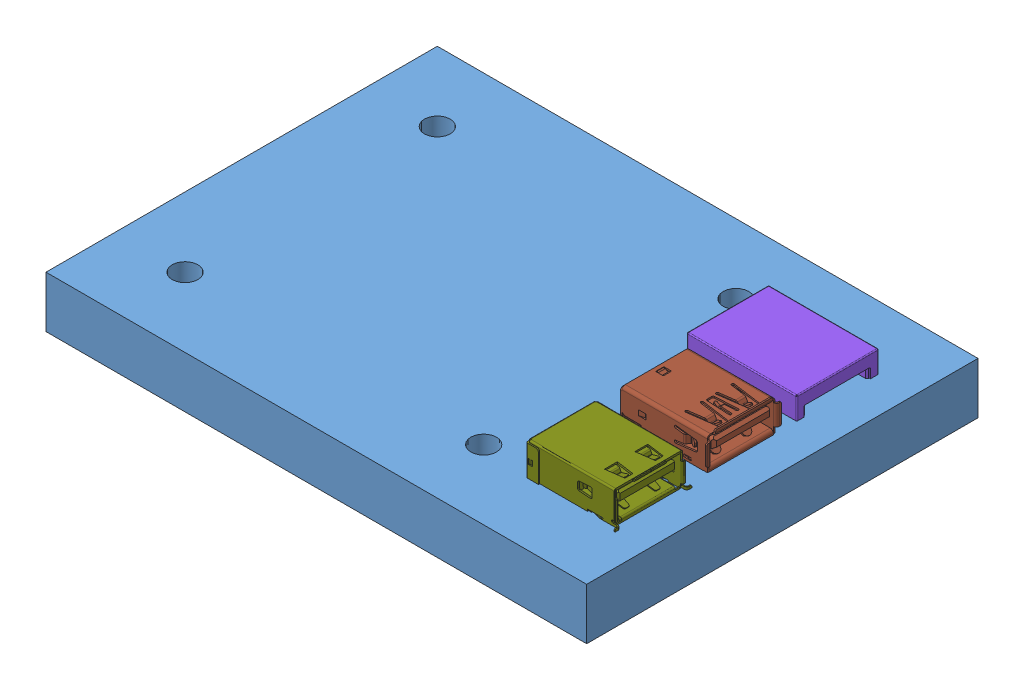
SolidWorks assembly Pi Alignment, configuration Default. Lengths in mm.
Overall size (105 19.92 76).
21 component instances, 19 part files, 7 mates.
Components (placement in the parent):
- Raspberry Pi 4 Model B-1: Raspberry Pi 4 Model B [Default] at origin size (89 19.92 58.4)
  - PCB, RPi4ModelB.STEP-1: PCB, RPi4ModelB.STEP [Default] at origin size (85 1.6 56)
  - Broadcom BCM2711B0 CPU, RPi4ModelB.STEP-1: Broadcom BCM2711B0 CPU, RPi4ModelB.STEP [Default] at (-13.25 0.8 -4.5) size (15 2.3 15)
  - 2.54 mm DUPONT MALE PIN HEADER, POE, 2X2, RPi4ModelB.STEP-1: 2.54 mm DUPONT MALE PIN HEADER, POE, 2X2, RPi4ModelB.STEP [Default] at (19 0.8 -18.36) size (5.08 11.3 5.08)
  - 2.54 mm DUPONT MALE PIN HEADER, IO, 2X20, RPi4ModelB.STEP-1: 2.54 mm DUPONT MALE PIN HEADER, IO, 2X20, RPi4ModelB.STEP [Default] at (-10 0.8 -24.5) size (50.8 11.3 5.08)
  - Camera Connector, RPi4ModelB.STEP-1: Camera Connector, RPi4ModelB.STEP [Default] at (4 0.8 16.5) x (0 0 -1) z (1 0 0) size (22.4 5.68 5.07)
  - Microphone Plug, RPi4ModelB.STEP-1: Microphone Plug, RPi4ModelB.STEP [Default] at (11.5 0.8 21.65) size (7.23 7.55 15)
  - Display Connector, RPi4ModelB.STEP-1: Display Connector, RPi4ModelB.STEP [Default] at (-38.5 0.8 0) x (0 0 1) z (-1 0 0) size (22.4 5.68 5.07)
  - Gigabit Ethernet Port, RPi4ModelB.STEP-1: Gigabit Ethernet Port, RPi4ModelB.STEP [Default] at (45.5 7.55 -17.75) x (0 0 -1) z (1 0 0) size (16.33 17.24 21.6)
  - Female Micro HDMI Connector, RPi4ModelB.STEP-1: Female Micro HDMI Connector, RPi4ModelB.STEP [Default] at (-3 0.8 27.3875) size (6.5 3.51 7.5)
  - Female Micro HDMI Connector, RPi4ModelB.STEP-2: Female Micro HDMI Connector, RPi4ModelB.STEP [Default] at (-16.5 0.8 27.3875) size (6.5 3.51 7.5)
  - Female USB Type C Connector, RPi4ModelB.STEP-1: Female USB Type C Connector, RPi4ModelB.STEP [Default] at (-31.3 0.8 26.5419) size (8.94 3.96 7.9)
  - 2X USB3.0 PORTS, RPi4ModelB.STEP-1: 2X USB3.0 PORTS, RPi4ModelB.STEP [Default] at (37.07 0.8 1) size (17.48 19.42 15.69)
  - 91D77 D9WHV 778K, 4 GB LPDDR4 SDRAM, RPi4ModelB.STEP-1: 91D77 D9WHV 778K, 4 GB LPDDR4 SDRAM, RPi4ModelB.STEP [Default] at (2.25 0.8 -4.5) size (10 0.8 14.5)
  - Cypress CYW43455 Wireless Module Cover, RPi4ModelB.STEP-1: Cypress CYW43455 Wireless Module Cover, RPi4ModelB.STEP [Default] at (-30.5 0.8 -14.5) size (11 1.6 13)
  - SD Card Slot, RPi4ModelB.STEP-1: SD Card Slot, RPi4ModelB.STEP [Default] at (-35.3 -0.8 0) x (0 0 -1) z (-1 0 0) size (11.95 1.45 11.4)
  - VIA VL805 PCIe USB 3.0 controller, RPi4ModelB.STEP-1: VIA VL805 PCIe USB 3.0 controller, RPi4ModelB.STEP [Default] at (17.5 0.8 4) size (8.8 0.8 8.8)
  - 2X USB2.0 PORTS, RPi4ModelB.STEP-1: 2X USB2.0 PORTS, RPi4ModelB.STEP [Default] at (37.065 0.65 19) size (17.87 19.17 15.35)
  - Broadcom BCM54213PE Gigabit Ethernet Transceiver, RPi4ModelB.STEP-1: Broadcom BCM54213PE Gigabit Ethernet Transceiver, RPi4ModelB.STEP [Default] at (16.5 0.8 -10) size (6.8 1 6.8)
  - MxL7704 Universal PMIC, RPi4ModelB.STEP-1: MxL7704 Universal PMIC, RPi4ModelB.STEP [Default] at (-32.5 0.8 16) size (5.4 0.8 5.4)
- Pi Jig-1: Pi Jig [Default] x (1 0 0) z (0 1 0) size (105 76 10)
Mates (geometry in assembly coordinates):
- Coincident1: coincident aligned: plane of Raspberry Pi 4 Model B-1 through (0 0 0) normal (0 0 1)
- Coincident2: coincident aligned: plane of Raspberry Pi 4 Model B-1 through (0 0 0) normal (0 1 0)
- Coincident3: coincident aligned: plane of Raspberry Pi 4 Model B-1 through (0 0 0) normal (1 0 0)
- InPlace1: in place: plane of Pi Jig-1 through (0 0 0) normal (0 1 0); moOrthogonalPlaneRef_w of Pi Jig-1 through (0 0 0) normal (0 0 -1); plane of Pi Jig-1 through (0 0 0) normal (1 0 0); unknown of Pi Jig-1
- Coincident4: coincident aligned: 
- Coincident5: coincident aligned: plane of Pi Jig-1 through (0 0 0) normal (0 0 -1)
- Coincident6: coincident anti-aligned: plane of Pi Jig-1 through (0 0 0) normal (1 0 0)
